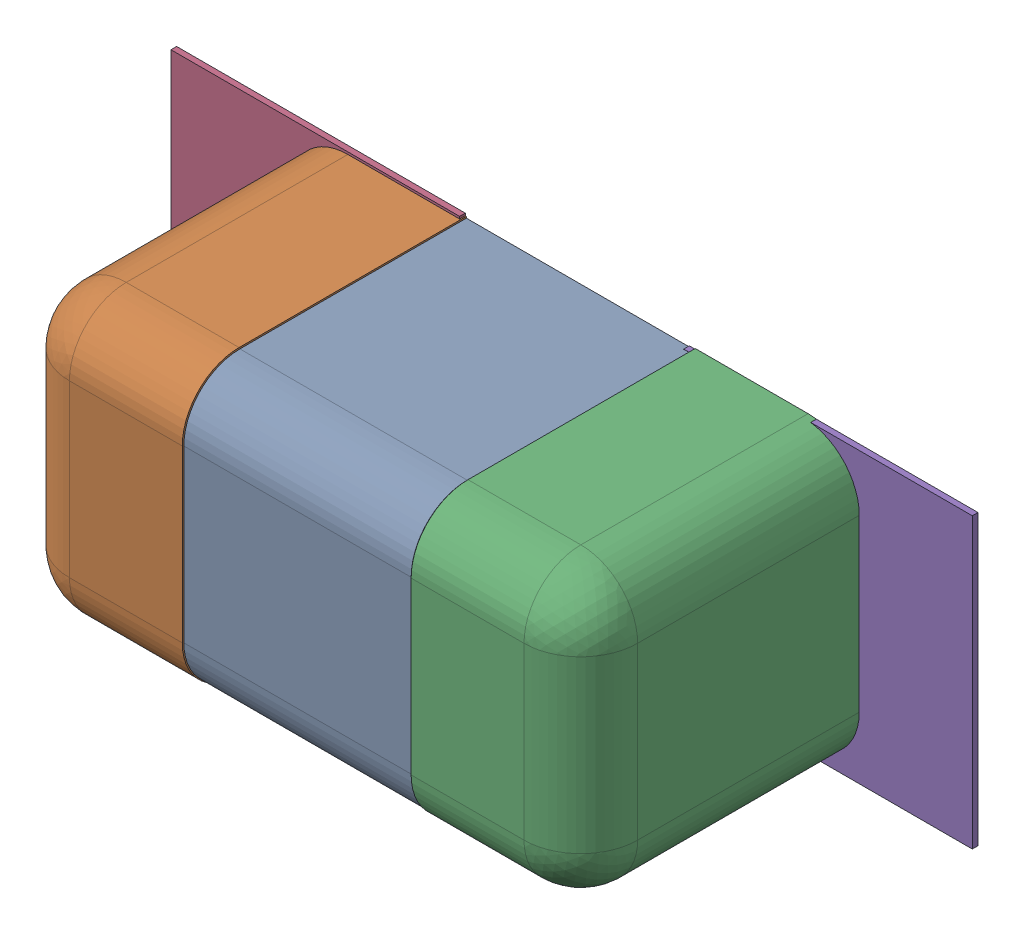
SolidWorks assembly C59, configuration Défaut. Lengths in mm.
Overall size (1.41 0.51 0.5).
8 component instances, 4 part files, 0 mates.
Components (placement in the parent):
- 6324936752-1: 6324936752 [Défaut] at (33.9344 -42.2148 0) x (1 0 0) z (0 -1 0) size (1 0.5 0.5)
  - Open CASCADE STEP translator 7.5 2.114.1.1-1: Open CASCADE STEP translator 7.5 2.114.1.1 [Défaut] at origin size (0.4 0.5 0.5)
  - Open CASCADE STEP translator 7.5 2.114.1.2-1: Open CASCADE STEP translator 7.5 2.114.1.2 [Défaut] at origin size (0.3 0.5 0.5)
  - Open CASCADE STEP translator 7.5 2.114.1.3-1: Open CASCADE STEP translator 7.5 2.114.1.3 [Défaut] at origin size (0.3 0.5 0.5)
- 6504207776-1: 6504207776 [Défaut] at (33.4771 -42.2148 0) size (0.51 0.51 0.01)
  - Extruded-1: Extruded [Défaut] at origin size (0.51 0.51 0.01)
- 6504207776-2: 6504207776 [Défaut] at (34.3794 -42.22 0) size (0.51 0.51 0.01)
  - Extruded-1: Extruded [Défaut] at origin size (0.51 0.51 0.01)
